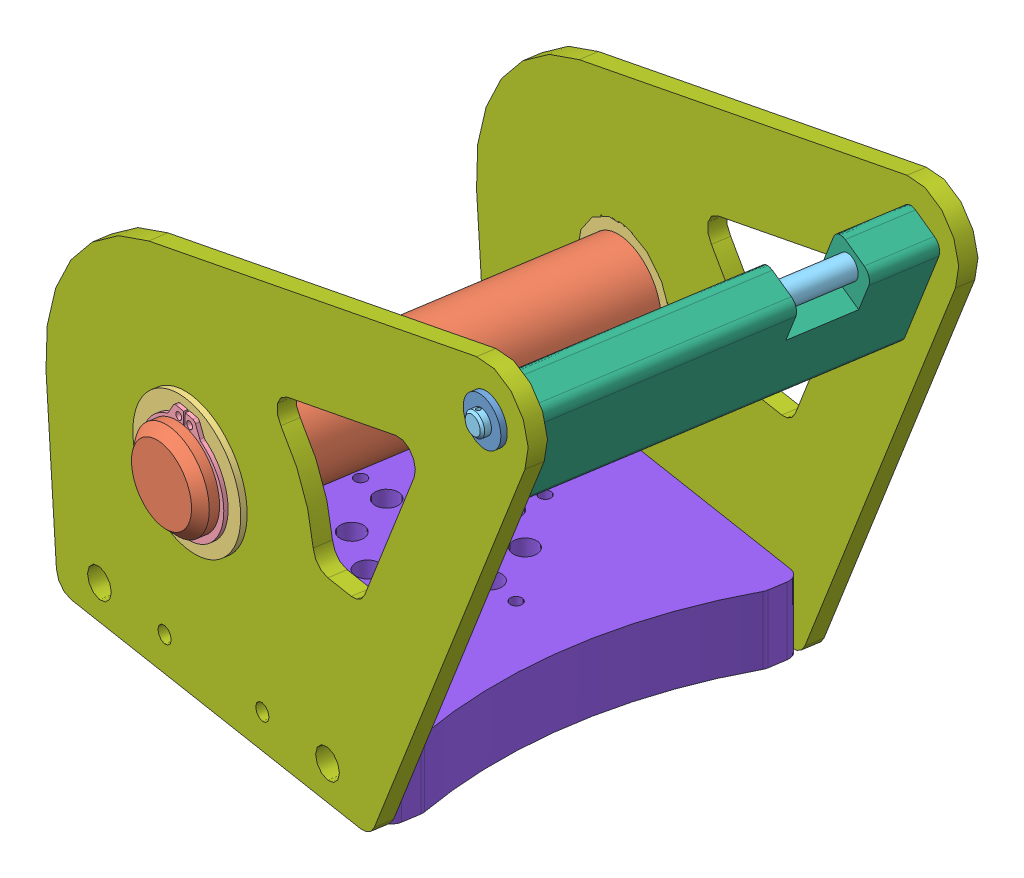
SolidWorks assembly UOR23-ARM-2-A-006_Hip, configuration Default. Lengths in mm.
Overall size (178.67 138.46 139.52).
12 component instances, 8 part files, 24 mates.
Components (placement in the parent):
- UOR23-ARM-2-P-005-1: UOR23-ARM-2-P-005 [6389K627] at (44.305 194.2 -12.9198) x (0.041096 -0.999135 0.006429) z (0.987129 0.041595 0.15442) size (12.7 6.35 12.7)
- UOR23-ARM-2-P-005-2: UOR23-ARM-2-P-005 [6389K627] at (61.9702 194.2 -125.8443) x (0.579534 0.80989 0.090658) z (0.800158 -0.586582 0.125171) size (12.7 6.35 12.7)
- UOR23-ARM-2-P-009-1: UOR23-ARM-2-P-009 [1346K38] at (-8.3512 124.2 -323.3395) x (0.983005 0.100275 0.153774) z (-0.154553 0 0.987984) size (25.4 25.4 126.8)
- UOR23-ARM-2-P-007-1: UOR23-ARM-2-P-007 [6389K559] at (-54.4934 124.2 -28.3751) x (0.485287 0.871053 0.075915) z (-0.860587 0.491189 -0.134624) size (36.51 6.35 36.51)
- UOR23-ARM-2-P-007-2: UOR23-ARM-2-P-007 [6389K559] at (-36.8283 124.2 -141.2997) x (-0.924034 -0.35393 -0.144549) z (-0.349677 0.935272 -0.054701) size (36.51 6.35 36.51)
- 98410A133_External Retaining Ring-1: 98410A133_External Retaining Ring [98410A133] at (-54.5758 124.2 -27.8481) x (-0.154553 0 0.987984) z (-0.987073 0.042935 -0.154411) size (1.07 30.68 28.04)
- 98410A133_External Retaining Ring-2: 98410A133_External Retaining Ring [98410A133] at (-36.745 124.2 -141.8319) x (-0.154553 0 0.987984) z (-0.987984 0 -0.154553) size (1.07 30.68 28.04)
- UOR23-ARM-2-P-011-1: UOR23-ARM-2-P-011 [1327K68] at (91.0556 194.2 -311.7733) x (0.984107 0.088505 0.153947) z (-0.154553 0 0.987984) size (6.35 6.35 118.92)
- UOR23-ARM-2-P-012-1: UOR23-ARM-2-P-012 [Default] at (39.2944 164.109 -20.1287) x (-0.905215 0.400667 -0.141606) z (0.154553 0 -0.987984) size (13 35 101.6)
- UOR23-ARM-2-P-004-1: UOR23-ARM-2-P-004 [Default] at (-87.8704 69.2 -112.4922) x (-0.987984 0 -0.154553) z (0.154553 0 -0.987984) size (163.46 138.46 4.76)
- UOR23-ARM-2-P-004-2: UOR23-ARM-2-P-004 [Default] at (-104.3087 69.2 -7.4098) x (-0.987984 0 -0.154553) z (0.154553 0 -0.987984) size (163.46 138.46 4.76)
- UOM20-4P018-1: UOM20-4P018 [Default] at (-39.8126 69.2 -77.8485) x (0.154553 0 -0.987984) z (0 1 0) size (101.6 105.67 19.05)
Mates (geometry in assembly coordinates):
- Coincident153: coincident aligned: plane of UOR23-ARM-2-P-009-1 through (-54.4934 124.2 -28.3751) normal (-0.154553 0 0.987984); plane of UOR23-ARM-2-P-007-1 through (-54.4934 124.2 -28.3751) normal (-0.154553 0 0.987984)
- Concentric127: concentric anti-aligned: circle of UOR23-ARM-2-P-009-1; circle of 98410A133_External Retaining Ring-1
- Coincident155: coincident anti-aligned: plane of UOR23-ARM-2-P-009-1 through (-54.4934 124.2 -28.3751) normal (-0.154553 0 0.987984); plane of 98410A133_External Retaining Ring-1 through (-54.4934 124.2 -28.3751) normal (0.154553 0 -0.987984)
- Concentric128: concentric anti-aligned: circle of UOR23-ARM-2-P-009-1; circle of 98410A133_External Retaining Ring-2
- Coincident156: coincident anti-aligned: plane of UOR23-ARM-2-P-009-1 through (-36.8275 124.2 -141.3049) normal (0.154553 0 -0.987984); plane of 98410A133_External Retaining Ring-2 through (-36.8275 124.2 -141.3049) normal (-0.154553 0 0.987984)
- Concentric164: concentric aligned: circle of UOR23-ARM-2-P-009-1; circle of UOR23-ARM-2-P-007-1
- Concentric213: concentric aligned: circle of UOR23-ARM-2-P-005-2; circle of UOR23-ARM-2-P-011-1
- Distance7: distance = 2.3098 mm aligned: plane of UOR23-ARM-2-P-011-1 through (62.3272 194.2 -128.1264) normal (0.154553 0 -0.987984); plane of UOR23-ARM-2-P-005-2 through (61.9702 194.2 -125.8443) normal (0.154553 0 -0.987984)
- Concentric222: concentric anti-aligned: circle of UOR23-ARM-2-P-011-1; circle of UOR23-ARM-2-P-012-1
- Concentric3: concentric aligned: circle of UOR23-ARM-2-P-004-1; circle of UOR23-ARM-2-P-004-2
- Coincident9: coincident aligned: plane of UOR23-ARM-2-P-004-1 through (-82.4977 69.2 -146.8371) normal (0 -1 0); plane of UOR23-ARM-2-P-004-2 through (-98.9361 69.2 -41.7547) normal (0 -1 0)
- Coincident214: coincident anti-aligned: plane of UOR23-ARM-2-P-004-1 through (-37.0736 124.2 -139.7312) normal (0.154553 0 -0.987984); plane of UOR23-ARM-2-P-005-2 through (61.7248 194.2 -124.2759) normal (-0.154553 0 0.987984)
- Concentric214: concentric aligned: circle of UOR23-ARM-2-P-004-1; circle of UOR23-ARM-2-P-005-2
- Coincident217: coincident anti-aligned: plane of UOR23-ARM-2-P-004-1 through (-37.0736 124.2 -139.7312) normal (0.154553 0 -0.987984); plane of UOR23-ARM-2-P-007-2 through (-37.0736 124.2 -139.7312) normal (-0.154553 0 0.987984)
- Concentric220: concentric aligned: circle of UOR23-ARM-2-P-004-1; circle of UOR23-ARM-2-P-007-2
- Coincident218: coincident anti-aligned: plane of UOR23-ARM-2-P-004-1 through (-37.8097 124.2 -135.026) normal (-0.154553 0 0.987984); plane of UOR23-ARM-2-P-012-1 through (54.9971 164.109 -120.5079) normal (0.154553 0 -0.987984)
- Coincident213: coincident anti-aligned: plane of UOR23-ARM-2-P-004-2 through (-54.248 124.2 -29.9435) normal (-0.154553 0 0.987984); plane of UOR23-ARM-2-P-005-1 through (44.5504 194.2 -14.4882) normal (0.154553 0 -0.987984)
- Concentric212: concentric anti-aligned: circle of UOR23-ARM-2-P-004-2; circle of UOR23-ARM-2-P-005-1
- Coincident216: coincident anti-aligned: plane of UOR23-ARM-2-P-004-2 through (-54.248 124.2 -29.9435) normal (-0.154553 0 0.987984); plane of UOR23-ARM-2-P-007-1 through (-54.248 124.2 -29.9435) normal (0.154553 0 -0.987984)
- Parallel9: parallel aligned: plane of UOR23-ARM-2-P-004-2 through (5.7903 69.2 -25.372) normal (0.905215 -0.400667 0.141606); plane of UOR23-ARM-2-P-012-1 through (54.9971 164.109 -120.5079) normal (0.905215 -0.400667 0.141606)
- Coincident3: coincident aligned: plane of UOR23-ARM-2-P-004-1 through (-82.4977 69.2 -146.8371) normal (0 -1 0); plane of UOM20-4P018-1 through (-39.8126 69.2 -77.8485) normal (0 -1 0)
- Coincident4: coincident anti-aligned: plane of UOR23-ARM-2-P-004-1 through (-37.8097 124.2 -135.026) normal (-0.154553 0 0.987984); plane of UOM20-4P018-1 through (-31.034 149.5794 -133.966) normal (0.154553 0 -0.987984)
- Coincident5: coincident aligned: cylinder of UOR23-ARM-2-P-004-1 through (-8.5753 78.725 -27.6182) axis (0.154553 0 -0.987984) radius 4.025; circle of UOM20-4P018-1
- Coincident10: coincident anti-aligned: plane of UOR23-ARM-2-P-004-2 through (-53.512 124.2 -34.6488) normal (0.154553 0 -0.987984); plane of UOM20-4P018-1 through (-46.7363 149.5794 -33.5889) normal (-0.154553 0 0.987984)
